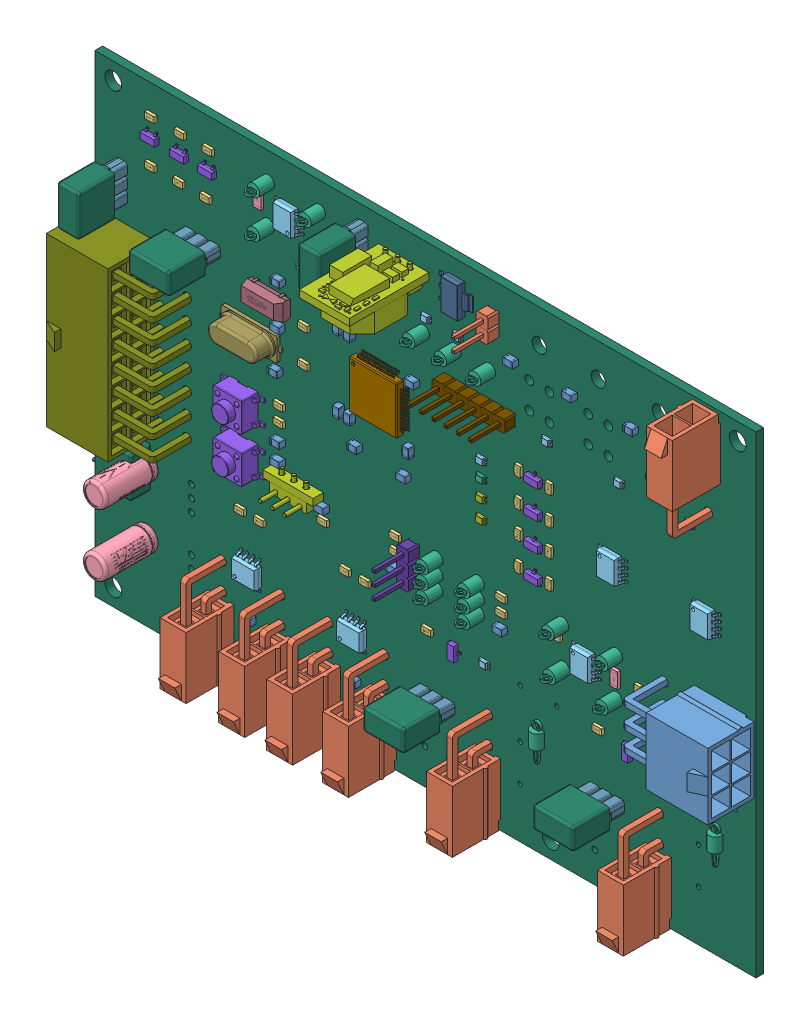
SolidWorks assembly Master_Board.step, configuration Default. Lengths in mm.
Overall size (137.77 98.3 40.09).
423 component instances, 33 part files, 0 mates.
Components (placement in the parent):
- 649004227222.step-1: 649004227222.step [Default] at (189.992 -45.085 6.984) x (-1 0 0) z (0 0 1) size (2.32 1.28 1.28)
  - COMPOUND.step-1: COMPOUND.step [Default] at origin size (2.32 1.28 1.28)
- male_header_2_54_1X2.step-1: male_header_2_54_1X2.step [Default] at (168.148 -44.45 1.65) x (0 -1 0) z (0 0 1) size (5.08 2.49 11.54)
  - COMPOUND-0.step-1: COMPOUND-0.step [Default] at origin size (5.08 2.49 11.54)
- DO-214AA_SMB.step-1: DO-214AA_SMB.step [Default] at (180.086 -123.444 -0.05) x (-1 0 0) z (0 0 -1) size (4.6 10.16 3.76)
  - SOLID.step-1: SOLID.step [Default] at origin size (4.6 10.16 3.76)
- C0805.step-1: C0805.step [Default] at (123.444 -76.6953 1.65) size (2.32 1.28 1.28)
  - COMPOUND.step-1: COMPOUND.step [Default] at origin size (2.32 1.28 1.28)
- C0805.step-2: C0805.step [Default] at (123.97 -89.1667 1.65) x (-1 0 0) z (0 0 1) size (2.32 1.28 1.28)
  - COMPOUND.step-1: COMPOUND.step [Default] at origin size (2.32 1.28 1.28)
- C0805.step-3: C0805.step [Default] at (112.776 -76.4413 1.65) size (2.32 1.28 1.28)
  - COMPOUND.step-1: COMPOUND.step [Default] at origin size (2.32 1.28 1.28)
- C0805.step-4: C0805.step [Default] at (123.934 -68.5673 1.65) size (2.32 1.28 1.28)
  - COMPOUND.step-1: COMPOUND.step [Default] at origin size (2.32 1.28 1.28)
- C0805.step-5: C0805.step [Default] at (148.1 -99.8347 1.65) x (-1 0 0) z (0 0 1) size (2.32 1.28 1.28)
  - COMPOUND.step-1: COMPOUND.step [Default] at origin size (2.32 1.28 1.28)
- C0805.step-6: C0805.step [Default] at (136.6393 -77.234 1.65) x (0 1 0) z (0 0 1) size (2.32 1.28 1.28)
  - COMPOUND.step-1: COMPOUND.step [Default] at origin size (2.32 1.28 1.28)
- C0805.step-7: C0805.step [Default] at (138.9253 -77.234 1.65) x (0 1 0) z (0 0 1) size (2.32 1.28 1.28)
  - COMPOUND.step-1: COMPOUND.step [Default] at origin size (2.32 1.28 1.28)
- C0805.step-8: C0805.step [Default] at (123.97 -60.2107 1.65) x (-1 0 0) z (0 0 1) size (2.32 1.28 1.28)
  - COMPOUND.step-1: COMPOUND.step [Default] at origin size (2.32 1.28 1.28)
- C0805.step-9: C0805.step [Default] at (136.6647 -62.212 1.65) x (0 -1 0) z (0 0 1) size (2.32 1.28 1.28)
  - COMPOUND.step-1: COMPOUND.step [Default] at origin size (2.32 1.28 1.28)
- C0805.step-10: C0805.step [Default] at (139.972 -82.0547 1.65) x (-1 0 0) z (0 0 1) size (2.32 1.28 1.28)
  - COMPOUND.step-1: COMPOUND.step [Default] at origin size (2.32 1.28 1.28)
- C0805.step-11: C0805.step [Default] at (138.9507 -62.23 1.65) x (0 -1 0) z (0 0 1) size (2.32 1.28 1.28)
  - COMPOUND.step-1: COMPOUND.step [Default] at origin size (2.32 1.28 1.28)
- C0805.step-12: C0805.step [Default] at (170.162 -99.8093 1.65) size (2.32 1.28 1.28)
  - COMPOUND.step-1: COMPOUND.step [Default] at origin size (2.32 1.28 1.28)
- C0805.step-13: C0805.step [Default] at (150.132 -82.3087 1.65) x (-1 0 0) z (0 0 1) size (2.32 1.28 1.28)
  - COMPOUND.step-1: COMPOUND.step [Default] at origin size (2.32 1.28 1.28)
- C0805.step-14: C0805.step [Default] at (151.1427 -77.216 1.65) x (0 -1 0) z (0 0 1) size (2.32 1.28 1.28)
  - COMPOUND.step-1: COMPOUND.step [Default] at origin size (2.32 1.28 1.28)
- C0805.step-15: C0805.step [Default] at (151.874 -64.5033 1.65) size (2.32 1.28 1.28)
  - COMPOUND.step-1: COMPOUND.step [Default] at origin size (2.32 1.28 1.28)
- C0805.step-16: C0805.step [Default] at (123.952 -92.7227 1.65) x (-1 0 0) z (0 0 1) size (2.32 1.28 1.28)
  - COMPOUND.step-1: COMPOUND.step [Default] at origin size (2.32 1.28 1.28)
- C0805.step-17: C0805.step [Default] at (147.338 -43.4213 -0.05) x (-1 0 0) z (0 0 -1) size (2.32 1.28 1.28)
  - COMPOUND.step-1: COMPOUND.step [Default] at origin size (2.32 1.28 1.28)
- C0805.step-18: C0805.step [Default] at (151.874 -43.4467 -0.05) x (1 0 0) z (0 0 -1) size (2.32 1.28 1.28)
  - COMPOUND.step-1: COMPOUND.step [Default] at origin size (2.32 1.28 1.28)
- C0805.step-19: C0805.step [Default] at (161.0487 -46.228 -0.05) x (0 1 0) z (0 0 -1) size (2.32 1.28 1.28)
  - COMPOUND.step-1: COMPOUND.step [Default] at origin size (2.32 1.28 1.28)
- C0805.step-20: C0805.step [Default] at (161.036 -41.6687 -0.05) x (1 0 0) z (0 0 -1) size (2.32 1.28 1.28)
  - COMPOUND.step-1: COMPOUND.step [Default] at origin size (2.32 1.28 1.28)
- C0805.step-21: C0805.step [Default] at (189.2427 -97.046 -0.05) x (0 1 0) z (0 0 -1) size (2.32 1.28 1.28)
  - COMPOUND.step-1: COMPOUND.step [Default] at origin size (2.32 1.28 1.28)
- C0805.step-22: C0805.step [Default] at (184.8993 -97.01 -0.05) x (0 -1 0) z (0 0 -1) size (2.32 1.28 1.28)
  - COMPOUND.step-1: COMPOUND.step [Default] at origin size (2.32 1.28 1.28)
- C0805.step-23: C0805.step [Default] at (180.5813 -97.01 -0.05) x (0 -1 0) z (0 0 -1) size (2.32 1.28 1.28)
  - COMPOUND.step-1: COMPOUND.step [Default] at origin size (2.32 1.28 1.28)
- C0805.step-24: C0805.step [Default] at (198.356 -101.1047 -0.05) x (1 0 0) z (0 0 -1) size (2.32 1.28 1.28)
  - COMPOUND.step-1: COMPOUND.step [Default] at origin size (2.32 1.28 1.28)
- C0805.step-25: C0805.step [Default] at (198.102 -92.9767 -0.05) x (1 0 0) z (0 0 -1) size (2.32 1.28 1.28)
  - COMPOUND.step-1: COMPOUND.step [Default] at origin size (2.32 1.28 1.28)
- C0805.step-26: C0805.step [Default] at (124.4727 -47.77 -0.05) x (0 1 0) z (0 0 -1) size (2.32 1.28 1.28)
  - COMPOUND.step-1: COMPOUND.step [Default] at origin size (2.32 1.28 1.28)
- C0805.step-27: C0805.step [Default] at (128.7907 -47.77 -0.05) x (0 1 0) z (0 0 -1) size (2.32 1.28 1.28)
  - COMPOUND.step-1: COMPOUND.step [Default] at origin size (2.32 1.28 1.28)
- C0805.step-28: C0805.step [Default] at (132.8547 -47.77 -0.05) x (0 1 0) z (0 0 -1) size (2.32 1.28 1.28)
  - COMPOUND.step-1: COMPOUND.step [Default] at origin size (2.32 1.28 1.28)
- C0805.step-29: C0805.step [Default] at (116.096 -51.5493 -0.05) x (-1 0 0) z (0 0 -1) size (2.32 1.28 1.28)
  - COMPOUND.step-1: COMPOUND.step [Default] at origin size (2.32 1.28 1.28)
- C0805.step-30: C0805.step [Default] at (116.096 -43.9293 -0.05) x (-1 0 0) z (0 0 -1) size (2.32 1.28 1.28)
  - COMPOUND.step-1: COMPOUND.step [Default] at origin size (2.32 1.28 1.28)
- C0805.step-31: C0805.step [Default] at (133.096 -96.5073 1.65) size (2.32 1.28 1.28)
  - COMPOUND.step-1: COMPOUND.step [Default] at origin size (2.32 1.28 1.28)
- C0805.step-32: C0805.step [Default] at (117.856 -124.1933 1.65) size (2.32 1.28 1.28)
  - COMPOUND.step-1: COMPOUND.step [Default] at origin size (2.32 1.28 1.28)
- C0805.step-33: C0805.step [Default] at (139.7 -124.4473 1.65) size (2.32 1.28 1.28)
  - COMPOUND.step-1: COMPOUND.step [Default] at origin size (2.32 1.28 1.28)
- 5x11x2x0_5.step-1: 5x11x2x0_5.step [Default] at (96.266 -120.412 1.65) x (0 1 0) z (0 0 1) size (4.99 5.01 31.22)
  - COMPOUND-2.step-1: COMPOUND-2.step [Default] at origin size (4.99 5.01 31.22)
- C0805.step-34: C0805.step [Default] at (117.874 -129.0447 1.65) x (-1 0 0) z (0 0 1) size (2.32 1.28 1.28)
  - COMPOUND.step-1: COMPOUND.step [Default] at origin size (2.32 1.28 1.28)
- C0805.step-35: C0805.step [Default] at (139.7 -129.2987 1.65) x (-1 0 0) z (0 0 1) size (2.32 1.28 1.28)
  - COMPOUND.step-1: COMPOUND.step [Default] at origin size (2.32 1.28 1.28)
- C0805.step-36: C0805.step [Default] at (102.0953 -120.396 -0.05) x (0 -1 0) z (0 0 -1) size (2.32 1.28 1.28)
  - COMPOUND.step-1: COMPOUND.step [Default] at origin size (2.32 1.28 1.28)
- C0805.step-37: C0805.step [Default] at (102.1207 -107.696 -0.05) x (0 1 0) z (0 0 -1) size (2.32 1.28 1.28)
  - COMPOUND.step-1: COMPOUND.step [Default] at origin size (2.32 1.28 1.28)
- C0805.step-38: C0805.step [Default] at (117.874 -112.5093 -0.05) x (-1 0 0) z (0 0 -1) size (2.32 1.28 1.28)
  - COMPOUND.step-1: COMPOUND.step [Default] at origin size (2.32 1.28 1.28)
- C0805.step-39: C0805.step [Default] at (139.718 -112.5093 -0.05) x (-1 0 0) z (0 0 -1) size (2.32 1.28 1.28)
  - COMPOUND.step-1: COMPOUND.step [Default] at origin size (2.32 1.28 1.28)
- 5x11x2x0_5.step-2: 5x11x2x0_5.step [Default] at (96.266 -107.442 1.65) x (0 -1 0) z (0 0 1) size (4.99 5.01 31.22)
  - COMPOUND-2.step-1: COMPOUND-2.step [Default] at origin size (4.99 5.01 31.22)
- C0805.step-40: C0805.step [Default] at (89.3953 -107.678 -0.05) x (0 -1 0) z (0 0 -1) size (2.32 1.28 1.28)
  - COMPOUND.step-1: COMPOUND.step [Default] at origin size (2.32 1.28 1.28)
- C0805.step-41: C0805.step [Default] at (146.8247 -108.984 -0.05) x (0 1 0) z (0 0 -1) size (2.32 1.28 1.28)
  - COMPOUND.step-1: COMPOUND.step [Default] at origin size (2.32 1.28 1.28)
- C0805.step-42: C0805.step [Default] at (124.7013 -108.948 -0.05) x (0 -1 0) z (0 0 -1) size (2.32 1.28 1.28)
  - COMPOUND.step-1: COMPOUND.step [Default] at origin size (2.32 1.28 1.28)
- C0805.step-43: C0805.step [Default] at (132.8547 -108.966 -0.05) x (0 1 0) z (0 0 -1) size (2.32 1.28 1.28)
  - COMPOUND.step-1: COMPOUND.step [Default] at origin size (2.32 1.28 1.28)
- C0805.step-44: C0805.step [Default] at (111.0107 -108.984 -0.05) x (0 1 0) z (0 0 -1) size (2.32 1.28 1.28)
  - COMPOUND.step-1: COMPOUND.step [Default] at origin size (2.32 1.28 1.28)
- WL_SMCW-0805_GREEN.step-1: WL_SMCW-0805_GREEN.step [Default] at (165.896 -71.628 1.65) x (-1 0 0) z (0 0 1) size (2 1.25 0.7)
  - COMPOUND-5.step-1: COMPOUND-5.step [Default] at origin size (2 1.25 0.7)
- WL_SMCW-0805_YELLOW.step-1: WL_SMCW-0805_YELLOW.step [Default] at (165.896 -74.93 1.65) x (-1 0 0) z (0 0 1) size (2 1.25 0.7)
  - COMPOUND-13.step-1: COMPOUND-13.step [Default] at origin size (2 1.25 0.7)
- WL_SMCW-0805_RED.step-1: WL_SMCW-0805_RED.step [Default] at (165.878 -78.486 1.65) x (-1 0 0) z (0 0 1) size (2 1.25 0.7)
  - COMPOUND-7.step-1: COMPOUND-7.step [Default] at origin size (2 1.25 0.7)
- WL_SMCW-0805_GREEN.step-2: WL_SMCW-0805_GREEN.step [Default] at (147.794 -51.816 1.65) size (2 1.25 0.7)
  - COMPOUND-5.step-1: COMPOUND-5.step [Default] at origin size (2 1.25 0.7)
- WL_SMCW-0805_GREEN.step-3: WL_SMCW-0805_GREEN.step [Default] at (154.398 -51.816 1.65) size (2 1.25 0.7)
  - COMPOUND-5.step-1: COMPOUND-5.step [Default] at origin size (2 1.25 0.7)
- WL_SMCW-0805_GREEN.step-4: WL_SMCW-0805_GREEN.step [Default] at (161.02 -51.816 1.65) size (2 1.25 0.7)
  - COMPOUND-5.step-1: COMPOUND-5.step [Default] at origin size (2 1.25 0.7)
- SOT-23-3.step-1: SOT-23-3.step [Default] at (198.12 -96.774 -0.6088) x (0 -1 0) z (1 0 0) size (3 1.1 2.5)
  - SOLID-2.step-1: SOLID-2.step [Default] at origin size (3 1.1 2.5)
- SOT-23-3.step-2: SOT-23-3.step [Default] at (115.908 -47.752 -0.6088) x (0 1 0) z (-1 0 0) size (3 1.1 2.5)
  - SOLID-2.step-1: SOLID-2.step [Default] at origin size (3 1.1 2.5)
- WL_SMCW-0805_GREEN.step-5: WL_SMCW-0805_GREEN.step [Default] at (179.562 -61.468 1.65) size (2 1.25 0.7)
  - COMPOUND-5.step-1: COMPOUND-5.step [Default] at origin size (2 1.25 0.7)
- WL_SMCW-0805_GREEN.step-6: WL_SMCW-0805_GREEN.step [Default] at (194.548 -61.468 1.65) size (2 1.25 0.7)
  - COMPOUND-5.step-1: COMPOUND-5.step [Default] at origin size (2 1.25 0.7)
- WL_SMCW-0805_GREEN.step-7: WL_SMCW-0805_GREEN.step [Default] at (209.28 -61.468 1.65) size (2 1.25 0.7)
  - COMPOUND-5.step-1: COMPOUND-5.step [Default] at origin size (2 1.25 0.7)
- DO-214AA_SMB.step-2: DO-214AA_SMB.step [Default] at (216.916 -122.682 -0.05) x (-1 0 0) z (0 0 -1) size (4.6 10.16 3.76)
  - SOLID.step-1: SOLID.step [Default] at origin size (4.6 10.16 3.76)
- SOD-323.step-1: SOD-323.step [Default] at (214.656 -110.49 -0.05) x (-1 0 0) z (0 0 -1) size (2.6 1.35 1.1)
  - SOLID-9.step-1: SOLID-9.step [Default] at origin size (2.6 1.35 1.1)
- SOD-323.step-2: SOD-323.step [Default] at (177.546 -110.49 -0.05) x (-1 0 0) z (0 0 -1) size (2.6 1.35 1.1)
  - SOLID-9.step-1: SOLID-9.step [Default] at origin size (2.6 1.35 1.1)
- WL_SMCW-0805_GREEN.step-8: WL_SMCW-0805_GREEN.step [Default] at (203.216 -107.95 1.65) x (-1 0 0) z (0 0 1) size (2 1.25 0.7)
  - COMPOUND-5.step-1: COMPOUND-5.step [Default] at origin size (2 1.25 0.7)
- WL_SMCW-0805_GREEN.step-9: WL_SMCW-0805_GREEN.step [Default] at (166.5792 -108.019 1.65) x (-1 0 0) z (0 0 1) size (2 1.25 0.7)
  - COMPOUND-5.step-1: COMPOUND-5.step [Default] at origin size (2 1.25 0.7)
- DO-214AA_SMB.step-3: DO-214AA_SMB.step [Default] at (117.856 -121.666 -0.05) x (1 0 0) z (0 0 -1) size (4.6 10.16 3.76)
  - SOLID.step-1: SOLID.step [Default] at origin size (4.6 10.16 3.76)
- DO-214AA_SMB.step-4: DO-214AA_SMB.step [Default] at (139.7 -121.92 -0.05) x (1 0 0) z (0 0 -1) size (4.6 10.16 3.76)
  - SOLID.step-1: SOLID.step [Default] at origin size (4.6 10.16 3.76)
- WL_SMCW-0805_YELLOW.step-2: WL_SMCW-0805_YELLOW.step [Default] at (101.108 -111.76 -0.05) x (-1 0 0) z (0 0 -1) size (2 1.25 0.7)
  - COMPOUND-13.step-1: COMPOUND-13.step [Default] at origin size (2 1.25 0.7)
- WL_SMCW-0805_RED.step-2: WL_SMCW-0805_RED.step [Default] at (165.896 -82.296 1.65) x (-1 0 0) z (0 0 1) size (2 1.25 0.7)
  - COMPOUND-7.step-1: COMPOUND-7.step [Default] at origin size (2 1.25 0.7)
- Littelfuse_562.step-1: Littelfuse_562.step [Default] at (112.776 -61.722 4.698) x (-1 0 0) z (0 1 0) size (7.62 6.88 2.54)
  - SOLID-14.step-1: SOLID-14.step [Default] at origin size (1.77 6.88 1.78)
  - SOLID-15.step-1: SOLID-15.step [Default] at origin size (1.09 2.06 1.09)
  - SOLID-16.step-1: SOLID-16.step [Default] at origin size (1.77 6.88 1.78)
  - SOLID-17.step-1: SOLID-17.step [Default] at origin size (1.09 2.06 1.09)
  - SOLID-18.step-1: SOLID-18.step [Default] at origin size (7.62 3 2.54)
- Littelfuse_TE5_395.step-1: Littelfuse_TE5_395.step [Default] at (107.696 -61.722 5.333) x (-1 0 0) z (0 1 0) size (8.5 10 4.5)
  - COMPOUND-19.step-1: COMPOUND-19.step [Default] at origin size (8.5 10 4.5)
- Littelfuse_562.step-2: Littelfuse_562.step [Default] at (90.932 -64.008 4.698) x (0 1 0) z (1 0 0) size (7.62 6.88 2.54)
  - SOLID-14.step-1: SOLID-14.step [Default] at origin size (1.77 6.88 1.78)
  - SOLID-15.step-1: SOLID-15.step [Default] at origin size (1.09 2.06 1.09)
  - SOLID-16.step-1: SOLID-16.step [Default] at origin size (1.77 6.88 1.78)
  - SOLID-17.step-1: SOLID-17.step [Default] at origin size (1.09 2.06 1.09)
  - SOLID-18.step-1: SOLID-18.step [Default] at origin size (7.62 3 2.54)
- Littelfuse_TE5_395.step-2: Littelfuse_TE5_395.step [Default] at (90.932 -58.928 5.333) x (0 1 0) z (1 0 0) size (8.5 10 4.5)
  - COMPOUND-19.step-1: COMPOUND-19.step [Default] at origin size (8.5 10 4.5)
- Littelfuse_562.step-3: Littelfuse_562.step [Default] at (140.97 -50.038 4.698) x (0 1 0) z (1 0 0) size (7.62 6.88 2.54)
  - SOLID-14.step-1: SOLID-14.step [Default] at origin size (1.77 6.88 1.78)
  - SOLID-15.step-1: SOLID-15.step [Default] at origin size (1.09 2.06 1.09)
  - SOLID-16.step-1: SOLID-16.step [Default] at origin size (1.77 6.88 1.78)
  - SOLID-17.step-1: SOLID-17.step [Default] at origin size (1.09 2.06 1.09)
  - SOLID-18.step-1: SOLID-18.step [Default] at origin size (7.62 3 2.54)
- Littelfuse_TE5_395.step-3: Littelfuse_TE5_395.step [Default] at (140.97 -44.958 5.333) x (0 1 0) z (1 0 0) size (8.5 10 4.5)
  - COMPOUND-19.step-1: COMPOUND-19.step [Default] at origin size (8.5 10 4.5)
- Littelfuse_562.step-4: Littelfuse_562.step [Default] at (151.384 -119.634 4.698) x (1 0 0) z (0 -1 0) size (7.62 6.88 2.54)
  - SOLID-14.step-1: SOLID-14.step [Default] at origin size (1.77 6.88 1.78)
  - SOLID-15.step-1: SOLID-15.step [Default] at origin size (1.09 2.06 1.09)
  - SOLID-16.step-1: SOLID-16.step [Default] at origin size (1.77 6.88 1.78)
  - SOLID-17.step-1: SOLID-17.step [Default] at origin size (1.09 2.06 1.09)
  - SOLID-18.step-1: SOLID-18.step [Default] at origin size (7.62 3 2.54)
- Littelfuse_TE5_395.step-4: Littelfuse_TE5_395.step [Default] at (156.464 -119.634 5.333) x (1 0 0) z (0 -1 0) size (8.5 10 4.5)
  - COMPOUND-19.step-1: COMPOUND-19.step [Default] at origin size (8.5 10 4.5)
- Littelfuse_562.step-5: Littelfuse_562.step [Default] at (186.69 -119.634 4.698) x (1 0 0) z (0 -1 0) size (7.62 6.88 2.54)
  - SOLID-14.step-1: SOLID-14.step [Default] at origin size (1.77 6.88 1.78)
  - SOLID-15.step-1: SOLID-15.step [Default] at origin size (1.09 2.06 1.09)
  - SOLID-16.step-1: SOLID-16.step [Default] at origin size (1.77 6.88 1.78)
  - SOLID-17.step-1: SOLID-17.step [Default] at origin size (1.09 2.06 1.09)
  - SOLID-18.step-1: SOLID-18.step [Default] at origin size (7.62 3 2.54)
- Littelfuse_TE5_395.step-5: Littelfuse_TE5_395.step [Default] at (191.77 -119.634 5.333) x (1 0 0) z (0 -1 0) size (8.5 10 4.5)
  - COMPOUND-19.step-1: COMPOUND-19.step [Default] at origin size (8.5 10 4.5)
- 649016227222.step-1: 649016227222.step [Default] at (91.567 -83.82 6.73) x (0 -1 0) z (0 0 1) size (35.1 19.97 14.95)
  - COMPOUND-14.step-1: COMPOUND-14.step [Default] at origin size (35.1 19.97 14.95)
- male_header_2_54_1X3.step-1: male_header_2_54_1X3.step [Default] at (151.638 -99.822 1.65) x (0 1 0) z (0 0 1) size (7.62 2.49 11.54)
  - COMPOUND-20.step-1: COMPOUND-20.step [Default] at origin size (7.62 2.49 11.54)
- male_header_2_54_1X6.step-1: male_header_2_54_1X6.step [Default] at (171.704 -61.214 1.65) x (-1 0 0) z (0 0 1) size (15.24 2.49 11.54)
  - COMPOUND-16.step-1: COMPOUND-16.step [Default] at origin size (15.24 2.49 11.54)
- 649006227222.step-1: 649006227222.step [Default] at (216.535 -97.028 6.984) x (0 1 0) z (0 0 1) size (14.1 19.97 14.95)
  - COMPOUND-29.step-1: COMPOUND-29.step [Default] at origin size (14.1 19.97 14.95)
- 649004227222.step-2: 649004227222.step [Default] at (177.732 -45.151 6.984) x (-1 0 0) z (0 0 1) size (2.32 1.28 1.28)
  - COMPOUND.step-1: COMPOUND.step [Default] at origin size (2.32 1.28 1.28)
- 649004227222.step-3: 649004227222.step [Default] at (202.692 -44.831 6.984) x (-1 0 0) z (0 0 1) size (2.32 1.28 1.28)
  - COMPOUND.step-1: COMPOUND.step [Default] at origin size (2.32 1.28 1.28)
- 649002227222.step-1: 649002227222.step [Default] at (202.692 -129.921 6.984) size (5.7 19.97 14.95)
  - COMPOUND-6.step-1: COMPOUND-6.step [Default] at origin size (5.7 19.97 14.95)
- 649002227222.step-2: 649002227222.step [Default] at (167.132 -129.921 6.984) size (5.7 19.97 14.95)
  - COMPOUND-6.step-1: COMPOUND-6.step [Default] at origin size (5.7 19.97 14.95)
- 649002227222.step-3: 649002227222.step [Default] at (123.952 -129.921 6.984) size (5.7 19.97 14.95)
  - COMPOUND-6.step-1: COMPOUND-6.step [Default] at origin size (5.7 19.97 14.95)
- 649002227222.step-4: 649002227222.step [Default] at (145.542 -129.921 6.984) size (5.7 19.97 14.95)
  - COMPOUND-6.step-1: COMPOUND-6.step [Default] at origin size (5.7 19.97 14.95)
- 649002227222.step-5: 649002227222.step [Default] at (133.9196 -129.921 6.984) size (5.7 19.97 14.95)
  - COMPOUND-6.step-1: COMPOUND-6.step [Default] at origin size (5.7 19.97 14.95)
- 649002227222.step-6: 649002227222.step [Default] at (111.76 -129.921 6.984) size (5.7 19.97 14.95)
  - COMPOUND-6.step-1: COMPOUND-6.step [Default] at origin size (5.7 19.97 14.95)
- WE-TPC-SMD.step-1: WE-TPC-SMD.step [Default] at (89.408 -107.696 3.428) x (0 -1 0) z (0 0 1) size (8.5 10 4.5)
  - COMPOUND-19.step-1: COMPOUND-19.step [Default] at origin size (8.5 10 4.5)
- SOT-23-3.step-3: SOT-23-3.step [Default] at (177.038 -69.596 2.2088) x (-1 0 0) z (0 1 0) size (3 1.1 2.5)
  - SOLID-2.step-1: SOLID-2.step [Default] at origin size (3 1.1 2.5)
- SOT-23-3.step-4: SOT-23-3.step [Default] at (177.038 -75.438 2.2088) x (-1 0 0) z (0 1 0) size (3 1.1 2.5)
  - SOLID-2.step-1: SOLID-2.step [Default] at origin size (3 1.1 2.5)
- SOT-23-3.step-5: SOT-23-3.step [Default] at (177.038 -81.28 2.2088) x (-1 0 0) z (0 1 0) size (3 1.1 2.5)
  - SOLID-2.step-1: SOLID-2.step [Default] at origin size (3 1.1 2.5)
- SOT-23-3.step-6: SOT-23-3.step [Default] at (177.038 -87.122 2.2088) x (-1 0 0) z (0 1 0) size (3 1.1 2.5)
  - SOLID-2.step-1: SOLID-2.step [Default] at origin size (3 1.1 2.5)
- SOT-23-3.step-7: SOT-23-3.step [Default] at (196.596 -108.712 2.2088) x (0 1 0) z (1 0 0) size (3 1.1 2.5)
  - SOLID-2.step-1: SOLID-2.step [Default] at origin size (3 1.1 2.5)
- SOT-23-3.step-8: SOT-23-3.step [Default] at (160.358 -108.778 2.2088) x (0 1 0) z (1 0 0) size (3 1.1 2.5)
  - SOLID-2.step-1: SOLID-2.step [Default] at origin size (3 1.1 2.5)
- SOT-23-3.step-9: SOT-23-3.step [Default] at (109.286 -47.836 2.2088) x (1 0 0) z (0 -1 0) size (3 1.1 2.5)
  - SOLID-2.step-1: SOLID-2.step [Default] at origin size (3 1.1 2.5)
- SOT-23-3.step-10: SOT-23-3.step [Default] at (103.444 -47.836 2.2088) x (1 0 0) z (0 -1 0) size (3 1.1 2.5)
  - SOLID-2.step-1: SOLID-2.step [Default] at origin size (3 1.1 2.5)
- SOT-23-3.step-11: SOT-23-3.step [Default] at (97.348 -47.836 2.2088) x (1 0 0) z (0 -1 0) size (3 1.1 2.5)
  - SOLID-2.step-1: SOLID-2.step [Default] at origin size (3 1.1 2.5)
- R0805.step-1: R0805.step [Default] at (123.918 -82.804 1.904) x (0 1 0) z (1 0 0) size (1.25 0.6 2)
  - COMPOUND-1.step-1: COMPOUND-1.step [Default] at origin size (1.25 0.6 2)
- R0805.step-2: R0805.step [Default] at (129.048 -72.898 1.904) x (0 -1 0) z (-1 0 0) size (1.25 0.6 2)
  - COMPOUND-1.step-1: COMPOUND-1.step [Default] at origin size (1.25 0.6 2)
- R0805.step-3: R0805.step [Default] at (123.936 -85.852 1.904) x (0 1 0) z (1 0 0) size (1.25 0.6 2)
  - COMPOUND-1.step-1: COMPOUND-1.step [Default] at origin size (1.25 0.6 2)
- R0805.step-4: R0805.step [Default] at (148.098 -94.234 1.904) x (0 -1 0) z (-1 0 0) size (1.25 0.6 2)
  - COMPOUND-1.step-1: COMPOUND-1.step [Default] at origin size (1.25 0.6 2)
- R0805.step-5: R0805.step [Default] at (148.098 -97.028 1.904) x (0 -1 0) z (-1 0 0) size (1.25 0.6 2)
  - COMPOUND-1.step-1: COMPOUND-1.step [Default] at origin size (1.25 0.6 2)
- R0805.step-6: R0805.step [Default] at (129.048 -66.04 1.904) x (0 -1 0) z (-1 0 0) size (1.25 0.6 2)
  - COMPOUND-1.step-1: COMPOUND-1.step [Default] at origin size (1.25 0.6 2)
- R0805.step-7: R0805.step [Default] at (170.146 -94.234 1.904) x (0 1 0) z (1 0 0) size (1.25 0.6 2)
  - COMPOUND-1.step-1: COMPOUND-1.step [Default] at origin size (1.25 0.6 2)
- R0805.step-8: R0805.step [Default] at (170.146 -97.028 1.904) x (0 1 0) z (1 0 0) size (1.25 0.6 2)
  - COMPOUND-1.step-1: COMPOUND-1.step [Default] at origin size (1.25 0.6 2)
- R0805.step-9: R0805.step [Default] at (165.828 -71.7014 -0.304) x (0 -1 0) z (1 0 0) size (1.25 0.6 2)
  - COMPOUND-1.step-1: COMPOUND-1.step [Default] at origin size (1.25 0.6 2)
- R0805.step-10: R0805.step [Default] at (165.846 -75.0034 -0.304) x (0 -1 0) z (1 0 0) size (1.25 0.6 2)
  - COMPOUND-1.step-1: COMPOUND-1.step [Default] at origin size (1.25 0.6 2)
- R0805.step-11: R0805.step [Default] at (123.936 -98.552 1.904) x (0 1 0) z (1 0 0) size (1.25 0.6 2)
  - COMPOUND-1.step-1: COMPOUND-1.step [Default] at origin size (1.25 0.6 2)
- R0805.step-12: R0805.step [Default] at (123.936 -95.504 1.904) x (0 1 0) z (1 0 0) size (1.25 0.6 2)
  - COMPOUND-1.step-1: COMPOUND-1.step [Default] at origin size (1.25 0.6 2)
- R0805.step-13: R0805.step [Default] at (165.828 -78.5594 -0.304) x (0 -1 0) z (1 0 0) size (1.25 0.6 2)
  - COMPOUND-1.step-1: COMPOUND-1.step [Default] at origin size (1.25 0.6 2)
- R0805.step-14: R0805.step [Default] at (147.862 -51.816 -0.304) x (0 1 0) z (-1 0 0) size (1.25 0.6 2)
  - COMPOUND-1.step-1: COMPOUND-1.step [Default] at origin size (1.25 0.6 2)
- R0805.step-15: R0805.step [Default] at (154.466 -51.816 -0.304) x (0 1 0) z (-1 0 0) size (1.25 0.6 2)
  - COMPOUND-1.step-1: COMPOUND-1.step [Default] at origin size (1.25 0.6 2)
- R0805.step-16: R0805.step [Default] at (161.07 -51.816 -0.304) x (0 1 0) z (-1 0 0) size (1.25 0.6 2)
  - COMPOUND-1.step-1: COMPOUND-1.step [Default] at origin size (1.25 0.6 2)
- R0805.step-17: R0805.step [Default] at (181.594 -95.504 1.904) x (0 1 0) z (1 0 0) size (1.25 0.6 2)
  - COMPOUND-1.step-1: COMPOUND-1.step [Default] at origin size (1.25 0.6 2)
- R1206.step-1: R1206.step [Default] at (193.802 -96.976 1.904) x (1 0 0) z (0 -1 0) size (1.6 0.6 3.2)
  - COMPOUND-21.step-1: COMPOUND-21.step [Default] at origin size (1.6 0.6 3.2)
- R0805.step-18: R0805.step [Default] at (198.628 -96.74 1.904) x (1 0 0) z (0 -1 0) size (1.25 0.6 2)
  - COMPOUND-1.step-1: COMPOUND-1.step [Default] at origin size (1.25 0.6 2)
- R0805.step-19: R0805.step [Default] at (132.35 -49.276 1.904) x (0 -1 0) z (-1 0 0) size (1.25 0.6 2)
  - COMPOUND-1.step-1: COMPOUND-1.step [Default] at origin size (1.25 0.6 2)
- R1206.step-2: R1206.step [Default] at (119.634 -47.804 1.904) x (-1 0 0) z (0 1 0) size (1.6 0.6 3.2)
  - COMPOUND-21.step-1: COMPOUND-21.step [Default] at origin size (1.6 0.6 3.2)
- R0805.step-20: R0805.step [Default] at (133.08 -99.06 1.904) x (0 1 0) z (1 0 0) size (1.25 0.6 2)
  - COMPOUND-1.step-1: COMPOUND-1.step [Default] at origin size (1.25 0.6 2)
- R0805.step-21: R0805.step [Default] at (173.736 -69.562 1.904) x (1 0 0) z (0 -1 0) size (1.25 0.6 2)
  - COMPOUND-1.step-1: COMPOUND-1.step [Default] at origin size (1.25 0.6 2)
- R0805.step-22: R0805.step [Default] at (173.736 -75.404 1.904) x (1 0 0) z (0 -1 0) size (1.25 0.6 2)
  - COMPOUND-1.step-1: COMPOUND-1.step [Default] at origin size (1.25 0.6 2)
- R0805.step-23: R0805.step [Default] at (173.736 -81.042 1.904) x (-1 0 0) z (0 1 0) size (1.25 0.6 2)
  - COMPOUND-1.step-1: COMPOUND-1.step [Default] at origin size (1.25 0.6 2)
- R0805.step-24: R0805.step [Default] at (173.736 -86.902 1.904) x (-1 0 0) z (0 1 0) size (1.25 0.6 2)
  - COMPOUND-1.step-1: COMPOUND-1.step [Default] at origin size (1.25 0.6 2)
- R0805.step-25: R0805.step [Default] at (180.086 -69.562 1.904) x (1 0 0) z (0 -1 0) size (1.25 0.6 2)
  - COMPOUND-1.step-1: COMPOUND-1.step [Default] at origin size (1.25 0.6 2)
- R0805.step-26: R0805.step [Default] at (180.086 -75.422 1.904) x (1 0 0) z (0 -1 0) size (1.25 0.6 2)
  - COMPOUND-1.step-1: COMPOUND-1.step [Default] at origin size (1.25 0.6 2)
- R0805.step-27: R0805.step [Default] at (180.086 -80.992 1.904) x (1 0 0) z (0 -1 0) size (1.25 0.6 2)
  - COMPOUND-1.step-1: COMPOUND-1.step [Default] at origin size (1.25 0.6 2)
- R0805.step-28: R0805.step [Default] at (180.086 -86.834 1.904) x (1 0 0) z (0 -1 0) size (1.25 0.6 2)
  - COMPOUND-1.step-1: COMPOUND-1.step [Default] at origin size (1.25 0.6 2)
- R0805.step-29: R0805.step [Default] at (179.562 -61.468 -0.304) x (0 -1 0) z (1 0 0) size (1.25 0.6 2)
  - COMPOUND-1.step-1: COMPOUND-1.step [Default] at origin size (1.25 0.6 2)
- R0805.step-30: R0805.step [Default] at (194.53 -61.468 -0.304) x (0 -1 0) z (1 0 0) size (1.25 0.6 2)
  - COMPOUND-1.step-1: COMPOUND-1.step [Default] at origin size (1.25 0.6 2)
- R0805.step-31: R0805.step [Default] at (209.262 -61.468 -0.304) x (0 -1 0) z (1 0 0) size (1.25 0.6 2)
  - COMPOUND-1.step-1: COMPOUND-1.step [Default] at origin size (1.25 0.6 2)
- R0805.step-32: R0805.step [Default] at (203.216 -107.95 -0.304) x (0 1 0) z (-1 0 0) size (1.25 0.6 2)
  - COMPOUND-1.step-1: COMPOUND-1.step [Default] at origin size (1.25 0.6 2)
- R0805.step-33: R0805.step [Default] at (166.5972 -108.019 -0.304) x (0 1 0) z (-1 0 0) size (1.25 0.6 2)
  - COMPOUND-1.step-1: COMPOUND-1.step [Default] at origin size (1.25 0.6 2)
- R0805.step-34: R0805.step [Default] at (190.262 -107.95 1.904) x (0 -1 0) z (-1 0 0) size (1.25 0.6 2)
  - COMPOUND-1.step-1: COMPOUND-1.step [Default] at origin size (1.25 0.6 2)
- R0805.step-35: R0805.step [Default] at (154.72 -107.95 1.904) x (0 -1 0) z (-1 0 0) size (1.25 0.6 2)
  - COMPOUND-1.step-1: COMPOUND-1.step [Default] at origin size (1.25 0.6 2)
- R0805.step-36: R0805.step [Default] at (117.84 -127 -0.304) x (0 -1 0) z (1 0 0) size (1.25 0.6 2)
  - COMPOUND-1.step-1: COMPOUND-1.step [Default] at origin size (1.25 0.6 2)
- R0805.step-37: R0805.step [Default] at (119.872 -117.348 -0.304) x (0 -1 0) z (1 0 0) size (1.25 0.6 2)
  - COMPOUND-1.step-1: COMPOUND-1.step [Default] at origin size (1.25 0.6 2)
- R0805.step-38: R0805.step [Default] at (139.666 -127.254 -0.304) x (0 -1 0) z (1 0 0) size (1.25 0.6 2)
  - COMPOUND-1.step-1: COMPOUND-1.step [Default] at origin size (1.25 0.6 2)
- R0805.step-39: R0805.step [Default] at (141.698 -117.602 -0.304) x (0 -1 0) z (1 0 0) size (1.25 0.6 2)
  - COMPOUND-1.step-1: COMPOUND-1.step [Default] at origin size (1.25 0.6 2)
- R0805.step-40: R0805.step [Default] at (115.84 -105.664 1.904) x (0 -1 0) z (-1 0 0) size (1.25 0.6 2)
  - COMPOUND-1.step-1: COMPOUND-1.step [Default] at origin size (1.25 0.6 2)
- R0805.step-41: R0805.step [Default] at (119.872 -105.664 1.904) x (0 1 0) z (1 0 0) size (1.25 0.6 2)
  - COMPOUND-1.step-1: COMPOUND-1.step [Default] at origin size (1.25 0.6 2)
- R0805.step-42: R0805.step [Default] at (137.702 -105.664 1.904) x (0 -1 0) z (-1 0 0) size (1.25 0.6 2)
  - COMPOUND-1.step-1: COMPOUND-1.step [Default] at origin size (1.25 0.6 2)
- R0805.step-43: R0805.step [Default] at (141.716 -105.664 1.904) x (0 1 0) z (1 0 0) size (1.25 0.6 2)
  - COMPOUND-1.step-1: COMPOUND-1.step [Default] at origin size (1.25 0.6 2)
- R0805.step-44: R0805.step [Default] at (122.174 -108.932 -0.304) x (-1 0 0) z (0 -1 0) size (1.25 0.6 2)
  - COMPOUND-1.step-1: COMPOUND-1.step [Default] at origin size (1.25 0.6 2)
- R0805.step-45: R0805.step [Default] at (144.272 -108.932 -0.304) x (-1 0 0) z (0 -1 0) size (1.25 0.6 2)
  - COMPOUND-1.step-1: COMPOUND-1.step [Default] at origin size (1.25 0.6 2)
- R0805.step-46: R0805.step [Default] at (135.382 -108.932 -0.304) x (-1 0 0) z (0 -1 0) size (1.25 0.6 2)
  - COMPOUND-1.step-1: COMPOUND-1.step [Default] at origin size (1.25 0.6 2)
- R0805.step-47: R0805.step [Default] at (113.538 -108.95 -0.304) x (-1 0 0) z (0 -1 0) size (1.25 0.6 2)
  - COMPOUND-1.step-1: COMPOUND-1.step [Default] at origin size (1.25 0.6 2)
- R0805.step-48: R0805.step [Default] at (92.964 -110.506 -0.304) x (1 0 0) z (0 1 0) size (1.25 0.6 2)
  - COMPOUND-1.step-1: COMPOUND-1.step [Default] at origin size (1.25 0.6 2)
- R0805.step-49: R0805.step [Default] at (165.846 -82.3694 -0.304) x (0 -1 0) z (1 0 0) size (1.25 0.6 2)
  - COMPOUND-1.step-1: COMPOUND-1.step [Default] at origin size (1.25 0.6 2)
- R0805.step-50: R0805.step [Default] at (108.696 -53.086 1.904) x (0 1 0) z (1 0 0) size (1.25 0.6 2)
  - COMPOUND-1.step-1: COMPOUND-1.step [Default] at origin size (1.25 0.6 2)
- R0805.step-51: R0805.step [Default] at (109.186 -44.196 1.904) x (0 1 0) z (1 0 0) size (1.25 0.6 2)
  - COMPOUND-1.step-1: COMPOUND-1.step [Default] at origin size (1.25 0.6 2)
- R0805.step-52: R0805.step [Default] at (103.108 -53.086 1.904) x (0 1 0) z (1 0 0) size (1.25 0.6 2)
  - COMPOUND-1.step-1: COMPOUND-1.step [Default] at origin size (1.25 0.6 2)
- R0805.step-53: R0805.step [Default] at (103.362 -44.196 1.904) x (0 1 0) z (1 0 0) size (1.25 0.6 2)
  - COMPOUND-1.step-1: COMPOUND-1.step [Default] at origin size (1.25 0.6 2)
- R0805.step-54: R0805.step [Default] at (97.266 -53.086 1.904) x (0 1 0) z (1 0 0) size (1.25 0.6 2)
  - COMPOUND-1.step-1: COMPOUND-1.step [Default] at origin size (1.25 0.6 2)
- R0805.step-55: R0805.step [Default] at (97.266 -44.196 1.904) x (0 1 0) z (1 0 0) size (1.25 0.6 2)
  - COMPOUND-1.step-1: COMPOUND-1.step [Default] at origin size (1.25 0.6 2)
- SOIC-8.step-1: SOIC-8.step [Default] at (193.2178 -76.7719 1.65) x (0 -1 0) z (0 0 1) size (4.9 6 1.75)
  - SOLID-26.step-1: SOLID-26.step [Default] at origin size (4.9 6 1.75)
- SOIC-8.step-2: SOIC-8.step [Default] at (212.6742 -76.708 1.65) x (0 -1 0) z (0 0 1) size (4.9 6 1.75)
  - SOLID-26.step-1: SOLID-26.step [Default] at origin size (4.9 6 1.75)
- SOIC-8.step-3: SOIC-8.step [Default] at (212.6742 -76.708 -0.05) x (0 -1 0) z (0 0 -1) size (4.9 6 1.75)
  - SOLID-26.step-1: SOLID-26.step [Default] at origin size (4.9 6 1.75)
- SOIC-8.step-4: SOIC-8.step [Default] at (193.2178 -76.7719 -0.05) x (0 -1 0) z (0 0 -1) size (4.9 6 1.75)
  - SOLID-26.step-1: SOLID-26.step [Default] at origin size (4.9 6 1.75)
- ALQ112.step-1: ALQ112.step [Default] at (177.546 -117.348 1.904) x (-1 0 0) z (0 1 0) size (2.54 2.54 7.62)
  - COMPOUND-23.step-1: COMPOUND-23.step [Default] at origin size (2.54 2.54 7.62)
- ALQ112.step-2: ALQ112.step [Default] at (214.63 -117.348 1.904) x (-1 0 0) z (0 1 0) size (2.54 2.54 7.62)
  - COMPOUND-23.step-1: COMPOUND-23.step [Default] at origin size (2.54 2.54 7.62)
- R0402.step-1: R0402.step [Default] at (133.154 -94.234 1.9548) x (-1 0 0) z (0 -1 0) size (12.5 23.21 12.48)
  - COMPOUND-24.step-1: COMPOUND-24.step [Default] at origin size (12.5 23.21 12.48)
- PTS645S.step-1: PTS645S.step [Default] at (116.332 -85.852 1.65) size (9 6 5)
  - COMPOUND-22.step-1: COMPOUND-22.step [Default] at origin size (9 6 5)
- PTS645S.step-2: PTS645S.step [Default] at (116.332 -95.25 1.65) x (-1 0 0) z (0 0 1) size (9 6 5)
  - COMPOUND-22.step-1: COMPOUND-22.step [Default] at origin size (9 6 5)
- Test_Point_Keystone_5001_BLACK.step-1: Test_Point_Keystone_5001_BLACK.step [Default] at (156.464 -97.028 1.65) size (2.54 2.54 7.62)
  - COMPOUND-23.step-1: COMPOUND-23.step [Default] at origin size (2.54 2.54 7.62)
- Test_Point_Keystone_5001_BLACK.step-2: Test_Point_Keystone_5001_BLACK.step [Default] at (156.464 -94.234 1.65) size (2.54 2.54 7.62)
  - COMPOUND-23.step-1: COMPOUND-23.step [Default] at origin size (2.54 2.54 7.62)
- Test_Point_Keystone_5001_BLACK.step-3: Test_Point_Keystone_5001_BLACK.step [Default] at (156.464 -99.822 1.65) size (2.54 2.54 7.62)
  - COMPOUND-23.step-1: COMPOUND-23.step [Default] at origin size (2.54 2.54 7.62)
- Test_Point_Keystone_5001_BLACK.step-4: Test_Point_Keystone_5001_BLACK.step [Default] at (165.1 -94.234 1.65) size (2.54 2.54 7.62)
  - COMPOUND-23.step-1: COMPOUND-23.step [Default] at origin size (2.54 2.54 7.62)
- Test_Point_Keystone_5001_BLACK.step-5: Test_Point_Keystone_5001_BLACK.step [Default] at (165.1 -97.028 1.65) size (2.54 2.54 7.62)
  - COMPOUND-23.step-1: COMPOUND-23.step [Default] at origin size (2.54 2.54 7.62)
- Test_Point_Keystone_5001_BLACK.step-6: Test_Point_Keystone_5001_BLACK.step [Default] at (165.1 -99.822 1.65) size (2.54 2.54 7.62)
  - COMPOUND-23.step-1: COMPOUND-23.step [Default] at origin size (2.54 2.54 7.62)
- Test_Point_Keystone_5001_BLACK.step-7: Test_Point_Keystone_5001_BLACK.step [Default] at (147.066 -54.864 1.65) size (2.54 2.54 7.62)
  - COMPOUND-23.step-1: COMPOUND-23.step [Default] at origin size (2.54 2.54 7.62)
- Test_Point_Keystone_5001_BLACK.step-8: Test_Point_Keystone_5001_BLACK.step [Default] at (140.462 -54.864 1.65) size (2.54 2.54 7.62)
  - COMPOUND-23.step-1: COMPOUND-23.step [Default] at origin size (2.54 2.54 7.62)
- Test_Point_Keystone_5001_BLACK.step-9: Test_Point_Keystone_5001_BLACK.step [Default] at (153.67 -54.864 1.65) size (2.54 2.54 7.62)
  - COMPOUND-23.step-1: COMPOUND-23.step [Default] at origin size (2.54 2.54 7.62)
- Test_Point_Keystone_5001_BLACK.step-10: Test_Point_Keystone_5001_BLACK.step [Default] at (160.274 -54.864 1.65) size (2.54 2.54 7.62)
  - COMPOUND-23.step-1: COMPOUND-23.step [Default] at origin size (2.54 2.54 7.62)
- Test_Point_Keystone_5001_BLACK.step-11: Test_Point_Keystone_5001_BLACK.step [Default] at (167.386 -54.864 1.65) size (2.54 2.54 7.62)
  - COMPOUND-23.step-1: COMPOUND-23.step [Default] at origin size (2.54 2.54 7.62)
- Test_Point_Keystone_5001_BLACK.step-12: Test_Point_Keystone_5001_BLACK.step [Default] at (182.626 -92.964 1.65) x (-1 0 0) z (0 0 1) size (2.54 2.54 7.62)
  - COMPOUND-23.step-1: COMPOUND-23.step [Default] at origin size (2.54 2.54 7.62)
- Test_Point_Keystone_5001_BLACK.step-13: Test_Point_Keystone_5001_BLACK.step [Default] at (182.88 -100.838 1.65) x (-1 0 0) z (0 0 1) size (2.54 2.54 7.62)
  - COMPOUND-23.step-1: COMPOUND-23.step [Default] at origin size (2.54 2.54 7.62)
- Test_Point_Keystone_5001_BLACK.step-14: Test_Point_Keystone_5001_BLACK.step [Default] at (193.802 -92.964 1.65) x (-1 0 0) z (0 0 1) size (2.54 2.54 7.62)
  - COMPOUND-23.step-1: COMPOUND-23.step [Default] at origin size (2.54 2.54 7.62)
- Test_Point_Keystone_5001_BLACK.step-15: Test_Point_Keystone_5001_BLACK.step [Default] at (193.802 -100.838 1.65) x (-1 0 0) z (0 0 1) size (2.54 2.54 7.62)
  - COMPOUND-23.step-1: COMPOUND-23.step [Default] at origin size (2.54 2.54 7.62)
- Test_Point_Keystone_5001_BLACK.step-16: Test_Point_Keystone_5001_BLACK.step [Default] at (132.08 -51.816 1.65) x (-1 0 0) z (0 0 1) size (2.54 2.54 7.62)
  - COMPOUND-23.step-1: COMPOUND-23.step [Default] at origin size (2.54 2.54 7.62)
- Test_Point_Keystone_5001_BLACK.step-17: Test_Point_Keystone_5001_BLACK.step [Default] at (132.08 -43.942 1.65) x (-1 0 0) z (0 0 1) size (2.54 2.54 7.62)
  - COMPOUND-23.step-1: COMPOUND-23.step [Default] at origin size (2.54 2.54 7.62)
- Test_Point_Keystone_5001_BLACK.step-18: Test_Point_Keystone_5001_BLACK.step [Default] at (121.412 -51.816 1.65) x (-1 0 0) z (0 0 1) size (2.54 2.54 7.62)
  - COMPOUND-23.step-1: COMPOUND-23.step [Default] at origin size (2.54 2.54 7.62)
- Test_Point_Keystone_5001_BLACK.step-19: Test_Point_Keystone_5001_BLACK.step [Default] at (121.412 -43.942 1.65) x (-1 0 0) z (0 0 1) size (2.54 2.54 7.62)
  - COMPOUND-23.step-1: COMPOUND-23.step [Default] at origin size (2.54 2.54 7.62)
- LQFP-64.step-1: LQFP-64.step [Default] at (139.7635 -65.3415 1.904) x (0 -1 0) z (0 0 1) size (12 12 1.71)
  - SOLID-0.step-1: SOLID-0.step [Default] at origin size (12 12 1.71)
- mps_dcdc_oki_78sr_vert_a.step-1: mps_dcdc_oki_78sr_vert_a.step [Default] at (144.145 -43.561 3.555) x (1 0 0) z (0 -1 0) size (12.5 23.21 12.48)
  - COMPOUND-24.step-1: COMPOUND-24.step [Default] at origin size (12.5 23.21 12.48)
- SOT-223.step-1: SOT-223.step [Default] at (160.528 -44.704 2.285) x (0 1 0) z (1 0 0) size (6.5 1.68 6.96)
  - SOLID-25.step-1: SOLID-25.step [Default] at origin size (6.5 1.68 6.96)
- SOIC-8.step-5: SOIC-8.step [Default] at (187.706 -97.028 1.65) x (0 -1 0) z (0 0 1) size (4.9 6 1.75)
  - SOLID-26.step-1: SOLID-26.step [Default] at origin size (4.9 6 1.75)
- SOIC-8.step-6: SOIC-8.step [Default] at (125.984 -47.752 1.65) x (0 1 0) z (0 0 1) size (4.9 6 1.75)
  - SOLID-26.step-1: SOLID-26.step [Default] at origin size (4.9 6 1.75)
- SOIC-8.step-7: SOIC-8.step [Default] at (117.856 -115.57 1.65) size (4.9 6 1.75)
  - SOLID-26.step-1: SOLID-26.step [Default] at origin size (4.9 6 1.75)
- SOIC-8.step-8: SOIC-8.step [Default] at (139.7 -115.824 1.65) size (4.9 6 1.75)
  - SOLID-26.step-1: SOLID-26.step [Default] at origin size (4.9 6 1.75)
- SOT-23-5.step-1: SOT-23-5.step [Default] at (117.856 -109.474 -0.558) x (0 1 0) z (-1 0 0) size (3 1.1 2.5)
  - SOLID-8.step-1: SOLID-8.step [Default] at origin size (3 1.1 2.5)
- SOT-23-5.step-2: SOT-23-5.step [Default] at (139.78 -109.474 -0.558) x (0 1 0) z (-1 0 0) size (3 1.1 2.5)
  - SOLID-8.step-1: SOLID-8.step [Default] at origin size (3 1.1 2.5)
- HC49_US.step-1: HC49_US.step [Default] at (118.11 -72.644 1.65) x (-1 0 0) z (0 0 1) size (12.8 4.83 4.3)
  - SOLID-28.step-1: SOLID-28.step [Default] at origin size (12.8 4.83 4.3)
- ABS25.step-1: ABS25.step [Default] at (122.174 -64.262 3.047) x (-1 0 0) z (0 0 1) size (8 4 2.66)
  - SOLID-27.step-1: SOLID-27.step [Default] at origin size (8 4 2.66)
- R0805.step-56: R0805.step [Default] at (219.202 -48.548 -0.304) x (1 0 0) z (0 1 0) size (1.25 0.6 2)
  - COMPOUND-1.step-1: COMPOUND-1.step [Default] at origin size (1.25 0.6 2)
- 4-SOP.step-1: 4-SOP.step [Default] at (217.932 -55.118 -1.05) x (0 -1 0) z (1 0 0) size (6.86 2.05 4)
  - SOLID-33.step-1: SOLID-33.step [Default] at origin size (6.86 2.05 4)
- 649002227222.step-7: 649002227222.step [Default] at (212.852 -44.831 6.984) x (-1 0 0) z (0 0 1) size (5.7 19.97 14.95)
  - COMPOUND-6.step-1: COMPOUND-6.step [Default] at origin size (5.7 19.97 14.95)
- R0805.step-57: R0805.step [Default] at (217.892 -61.788 -0.304) x (1 0 0) z (0 1 0) size (1.25 0.6 2)
  - COMPOUND-1.step-1: COMPOUND-1.step [Default] at origin size (1.25 0.6 2)
- COMPOUND-34.step-1: COMPOUND-34.step [Default] at origin size (137.41 98.3 1.6)
